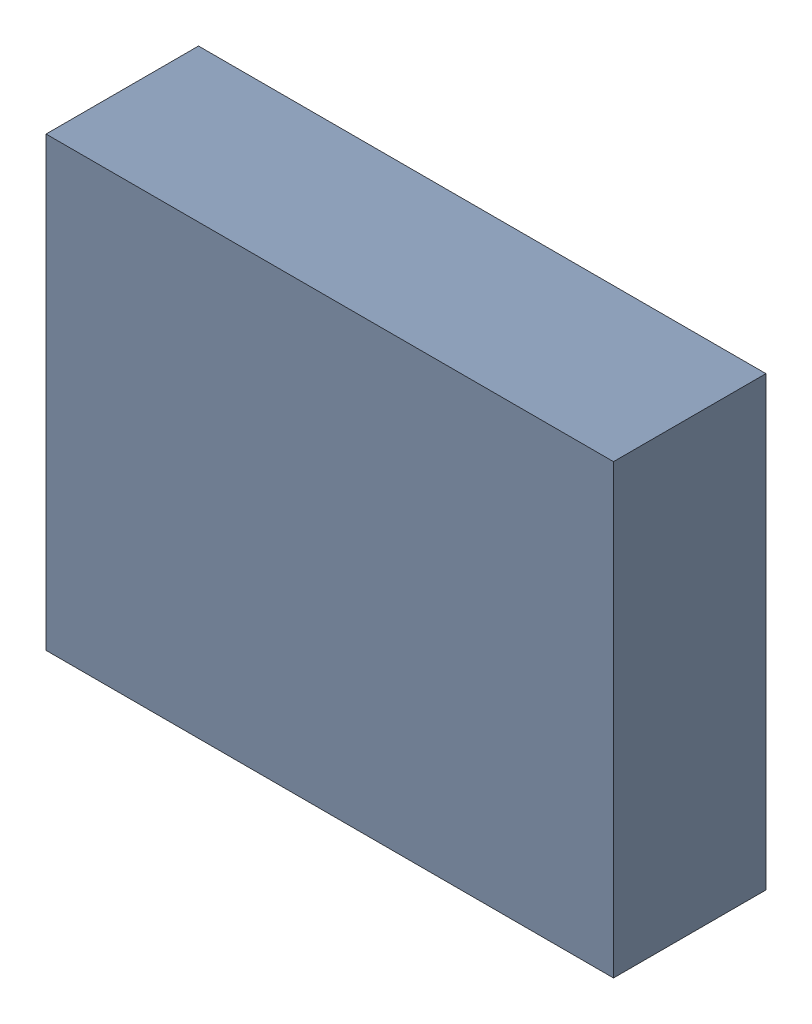
SolidWorks assembly PULL_A, configuration Default. Lengths in mm.
Overall size (3.35 2.64 0.9).
2 component instances, 1 part files, 0 mates.
Components (placement in the parent):
- 5920132160-1: 5920132160 [Default] at (46.277 43.877 0) size (3.35 2.64 0.9)
  - Extruded-1: Extruded [Default] at origin size (3.35 2.64 0.9)
